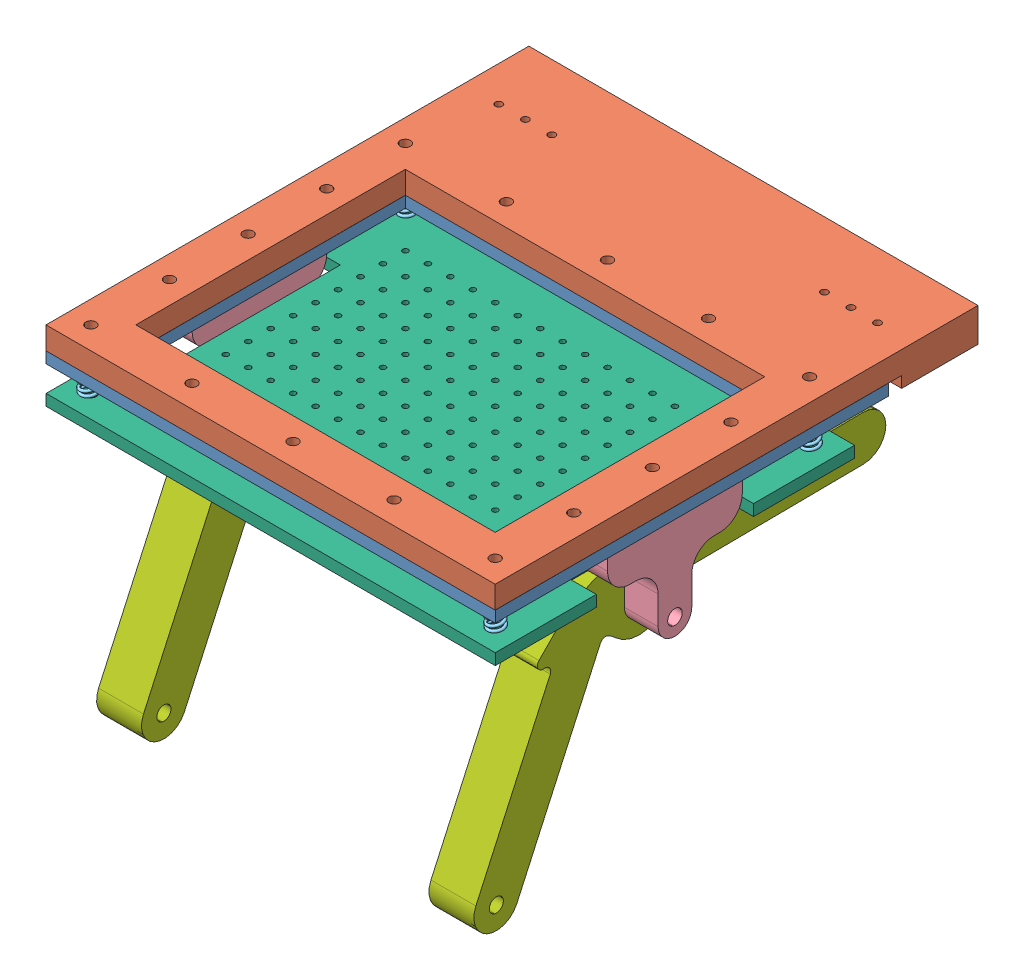
SolidWorks assembly FullBuild, configuration Default. Lengths in mm.
Overall size (254.06 190.47 273.05).
17 component instances, 7 part files, 25 mates.
Components (placement in the parent):
- BasePlate-1: BasePlate [Default] at (-55.7526 115.0278 286.3224) size (254 6.35 222.25)
- LockPlate-1: LockPlate [Default] at (198.1918 134.0778 286.3224) x (-1 0 0) z (0 0 1) size (254 19.05 273.05)
- HingeFull-1: HingeFull [Default] at (188.9093 74.9858 61.3518) x (0 -1 0) z (0.00278 0 0.999996) size (6 44 32)
  - HingePart-7: HingePart [Default] at (-40.0421 -47.6115 14.8207) size (6 44 19)
  - HingePart-8: HingePart [Default] at (-40.0421 -3.6115 -17.1793) x (1 0 0) z (0 0 -1) size (6 44 19)
- HingeFull-2: HingeFull [Default] at (4.7711 74.9858 61.3518) x (0 -1 0) z (0.00278 0 0.999996) size (6 44 32)
  - HingePart-7: HingePart [Default] at (-40.0421 -47.6115 14.8207) size (6 44 19)
  - HingePart-8: HingePart [Default] at (-40.0421 -3.6115 -17.1793) x (1 0 0) z (0 0 -1) size (6 44 19)
- Upright-1: Upright [Default] at (198.2474 115.0278 146.6224) x (0 0 1) z (0 1 0) size (76.2 19.05 57.28)
- Upright-2: Upright [Default] at (-55.7526 115.0278 222.8224) x (0 0 -1) z (0 1 0) size (76.2 19.05 57.28)
- 2006N234_302 Stainless Steel Corrosion-Resistant Compression Springs.step-1: 2006N234_302 Stainless Steel Corrosion-Resistant Compression Springs.step [Default] at (185.2701 115.0278 96.2341) x (-0.837169 0 -0.546944) z (-0.035299 0.997915 0.054029) size (9.62 9.62 16.11)
- 2006N234_302 Stainless Steel Corrosion-Resistant Compression Springs.step-2: 2006N234_302 Stainless Steel Corrosion-Resistant Compression Springs.step [Default] at (185.172 115.0278 274.1577) x (-0.837169 0 -0.546944) z (-0.035299 0.997915 0.054029) size (9.62 9.62 16.11)
- 2006N234_302 Stainless Steel Corrosion-Resistant Compression Springs.step-3: 2006N234_302 Stainless Steel Corrosion-Resistant Compression Springs.step [Default] at (-45.0104 115.0278 274.1221) x (-0.837169 0 -0.546944) z (-0.035299 0.997915 0.054029) size (9.62 9.62 16.11)
- 2006N234_302 Stainless Steel Corrosion-Resistant Compression Springs.step-4: 2006N234_302 Stainless Steel Corrosion-Resistant Compression Springs.step [Default] at (-43.1273 115.0278 95.9798) x (-0.837169 0 -0.546944) z (-0.035299 0.997915 0.054029) size (9.62 9.62 16.11)
- top plate-1: top plate [Default] at (-55.7526 94.2081 286.3224) size (254 6.35 203.2)
- CamArm-1: CamArm [Default] at (-35.4326 142.9312 131.2705) x (0 -0.009376 0.999956) z (0 0.999956 0.009376) size (234.14 25.4 148.25)
- CamArm-2: CamArm [Default] at (152.5274 142.9312 131.2705) x (0 -0.009376 0.999956) z (0 0.999956 0.009376) size (234.14 25.4 148.25)
Mates (geometry in assembly coordinates):
- Coincident1: coincident anti-aligned: plane of LockPlate-1 through (198.1918 115.0278 286.3224) normal (0 -1 0); plane of HingeFull-2/HingePart-8 through (1.1119 115.0278 44.1826) normal (0 1 0)
- Coincident2: coincident anti-aligned: plane of LockPlate-1 through (198.1918 115.0278 286.3224) normal (0 -1 0); plane of HingeFull-1/HingePart-8 through (185.2501 115.0278 44.1826) normal (0 1 0)
- Concentric4: concentric anti-aligned: cylinder of LockPlate-1 through (178.2668 134.0778 50.202) axis (0 -1 0) radius 1.75; cylinder of HingeFull-1/HingePart-8 through (178.2668 -11.9722 50.202) axis (0 1 0) radius 2
- Concentric5: concentric anti-aligned: cylinder of LockPlate-1 through (-5.8714 134.0778 50.202) axis (0 -1 0) radius 1.75; cylinder of HingeFull-2/HingePart-8 through (-5.8714 -11.9722 50.202) axis (0 1 0) radius 2
- Coincident3: coincident anti-aligned: plane of BasePlate-1 through (-55.7526 115.0278 286.3224) normal (0 -1 0); plane of HingeFull-1/HingePart-7 through (141.3392 115.0278 76.3048) normal (0 1 0)
- Concentric6: concentric aligned: cylinder of BasePlate-1 through (178.3224 112.3778 70.2019) axis (0 1 0) radius 1.75; cylinder of HingeFull-1/HingePart-7 through (178.3224 -11.9722 70.2019) axis (0 1 0) radius 2
- Concentric7: concentric aligned: cylinder of BasePlate-1 through (-5.8158 112.3778 70.2019) axis (0 1 0) radius 1.75; cylinder of HingeFull-2/HingePart-7 through (-5.8158 -11.9722 70.2019) axis (0 1 0) radius 2
- Concentric8: concentric anti-aligned: cylinder of BasePlate-1 through (190.6274 121.3778 210.1224) axis (0 1 0) radius 2.75; cylinder of Upright-1 through (190.6274 115.0278 210.1224) axis (0 -1 0) radius 3
- Coincident4: coincident anti-aligned: plane of BasePlate-1 through (-55.7526 115.0278 286.3224) normal (0 -1 0); plane of Upright-1 through (179.1974 115.0278 146.6224) normal (0 1 0)
- Coincident5: coincident aligned: plane of BasePlate-1 through (198.2474 121.3778 286.3224) normal (1 0 0); plane of Upright-1 through (198.2474 115.0278 146.6224) normal (1 0 0)
- Concentric9: concentric anti-aligned: circle of BasePlate-1; circle of Upright-2
- Coincident6: coincident anti-aligned: plane of BasePlate-1 through (-55.7526 115.0278 286.3224) normal (0 -1 0); plane of Upright-2 through (-36.7026 115.0278 222.8224) normal (0 1 0)
- Coincident7: coincident aligned: plane of BasePlate-1 through (-55.7526 121.3778 286.3224) normal (-1 0 0); plane of Upright-2 through (-55.7526 115.0278 222.8224) normal (-1 0 0)
- Coincident8: coincident anti-aligned: plane of BasePlate-1 through (-55.7526 115.0278 286.3224) normal (0 -1 0); plane of 2006N234_302 Stainless Steel Corrosion-Resistant Compression Springs.step-4 through (-53.5801 115.0278 82.1407) normal (0 1 0)
- Coincident9: coincident anti-aligned: plane of 2006N234_302 Stainless Steel Corrosion-Resistant Compression Springs.step-3 through (-55.4633 115.0278 260.283) normal (0 1 0); plane of BasePlate-1 through (-55.7526 115.0278 286.3224) normal (0 -1 0)
- Coincident10: coincident anti-aligned: plane of BasePlate-1 through (-55.7526 115.0278 286.3224) normal (0 -1 0); plane of 2006N234_302 Stainless Steel Corrosion-Resistant Compression Springs.step-2 through (174.7192 115.0278 260.3186) normal (0 1 0)
- Coincident11: coincident anti-aligned: plane of BasePlate-1 through (-55.7526 115.0278 286.3224) normal (0 -1 0); plane of 2006N234_302 Stainless Steel Corrosion-Resistant Compression Springs.step-1 through (174.8173 115.0278 82.395) normal (0 1 0)
- Concentric10: concentric aligned: cylinder of BasePlate-1 through (-43.0526 121.3778 95.8224) axis (0 -1 0) radius 3.05; cylinder of top plate-1 through (-43.0526 100.5581 95.8224) axis (0 -1 0) radius 3.1
- Coincident12: coincident anti-aligned: plane of 2006N234_302 Stainless Steel Corrosion-Resistant Compression Springs.step-4 through (-58.8181 100.5581 91.6207) normal (0 -1 0); plane of top plate-1 through (-55.7526 100.5581 286.3224) normal (0 1 0)
- Concentric11: concentric aligned: cylinder of BasePlate-1 through (-43.0526 121.3778 273.6224) axis (0 -1 0) radius 3.05; cylinder of top plate-1 through (-43.0526 100.5581 273.6224) axis (0 -1 0) radius 3.1
- Concentric12: concentric aligned: cylinder of Upright-2 through (-36.7026 67.2758 184.7224) axis (-1 0 0) radius 4.125; cylinder of CamArm-1 through (-10.0326 67.2758 184.7224) axis (-1 0 0) radius 4.05
- Concentric13: concentric anti-aligned: cylinder of Upright-1 through (179.1974 67.2758 184.7224) axis (1 0 0) radius 4.125; cylinder of CamArm-2 through (177.9274 67.2758 184.7224) axis (-1 0 0) radius 4.05
- Coincident13: coincident aligned: plane of top plate-1 through (177.9274 100.5581 229.1724) normal (1 0 0); plane of CamArm-2 through (177.9274 81.1934 57.8473) normal (1 0 0)
- Coincident14: coincident aligned: plane of top plate-1 through (-35.4326 100.5581 140.2724) normal (-1 0 0); plane of CamArm-1 through (-35.4326 81.1934 57.8473) normal (-1 0 0)
- Coincident15: coincident aligned: plane of CamArm-1 through (-10.0326 -38.317 276.9618) normal (0 0.414102 0.91023); plane of CamArm-2 through (177.9274 -38.317 276.9618) normal (0 0.414102 0.91023)
